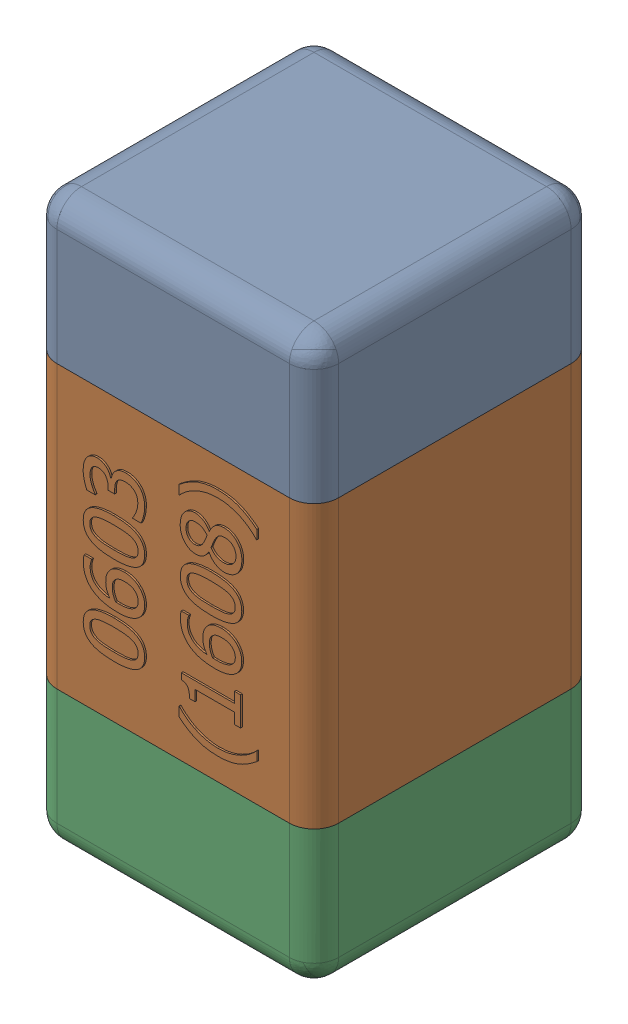
SolidWorks assembly C20, configuration Standard. Lengths in mm.
Overall size (0.81 1.61 0.81).
4 component instances, 3 part files, 0 mates.
Components (placement in the parent):
- C20-subassembly-1-1: C20-subassembly-1 [Standard] at (-10.8001 -8.1999 0) x (0 1 0) z (0 0 1) size (1.61 0.81 0.81)
  - User Library-0603_Cap-1: User Library-0603_Cap [Standard] at origin size (0.41 0.81 0.81)
  - User Library-0603_Cap-1-1: User Library-0603_Cap-1 [Standard] at origin size (0.8 0.8 0.81)
  - User Library-0603_Cap-2-1: User Library-0603_Cap-2 [Standard] at origin size (0.41 0.81 0.81)
